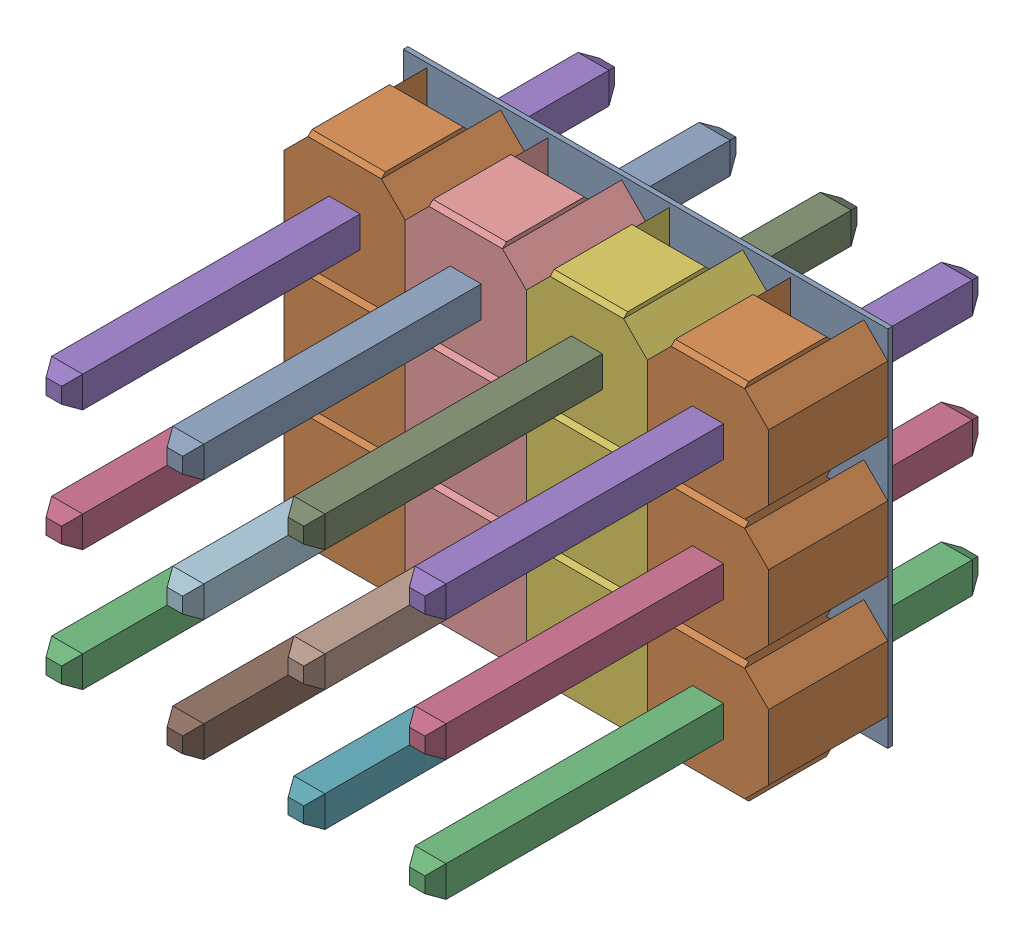
SolidWorks assembly 254-3X4-1, configuration ﾃﾞﾌｫﾙﾄ. Lengths in mm.
Overall size (10.16 7.62 11.6).
11 component instances, 2 part files, 0 mates.
Components (placement in the parent):
- PCB-1: PCB [ﾃﾞﾌｫﾙﾄ] at (-5.04 -3.81 0) size (10.16 7.62 11.6)
  - Board-1: Board [ﾃﾞﾌｫﾙﾄ] at origin size (10.16 7.62 0.1)
    - Open CASCADE STEP translator 6.8 6.1.1-1: Open CASCADE STEP translator 6.8 6.1.1 [ﾃﾞﾌｫﾙﾄ] at (0 0 -0.0965) size (10.16 7.62 0.1)
  - Z_RST3-1: Z_RST3 [ﾃﾞﾌｫﾙﾄ] at origin size (2.54 7.62 11.6)
    - DS1021-1x3SF11-1: DS1021-1x3SF11 [ﾃﾞﾌｫﾙﾄ] at (8.8901 1.2699 0) x (0 1 0) z (0 0 1) size (7.62 2.54 11.6)
  - Z_RST2-1: Z_RST2 [ﾃﾞﾌｫﾙﾄ] at origin size (2.54 7.62 11.6)
    - DS1021-1x3SF11-1: DS1021-1x3SF11 [ﾃﾞﾌｫﾙﾄ] at (6.3501 1.2699 0) x (0 1 0) z (0 0 1) size (7.62 2.54 11.6)
  - Z_RST1-1: Z_RST1 [ﾃﾞﾌｫﾙﾄ] at origin size (2.54 7.62 11.6)
    - DS1021-1x3SF11-1: DS1021-1x3SF11 [ﾃﾞﾌｫﾙﾄ] at (3.8101 1.2699 0) x (0 1 0) z (0 0 1) size (7.62 2.54 11.6)
  - Z_RST-1: Z_RST [ﾃﾞﾌｫﾙﾄ] at origin size (2.54 7.62 11.6)
    - DS1021-1x3SF11-1: DS1021-1x3SF11 [ﾃﾞﾌｫﾙﾄ] at (1.2701 1.2699 0) x (0 1 0) z (0 0 1) size (7.62 2.54 11.6)
